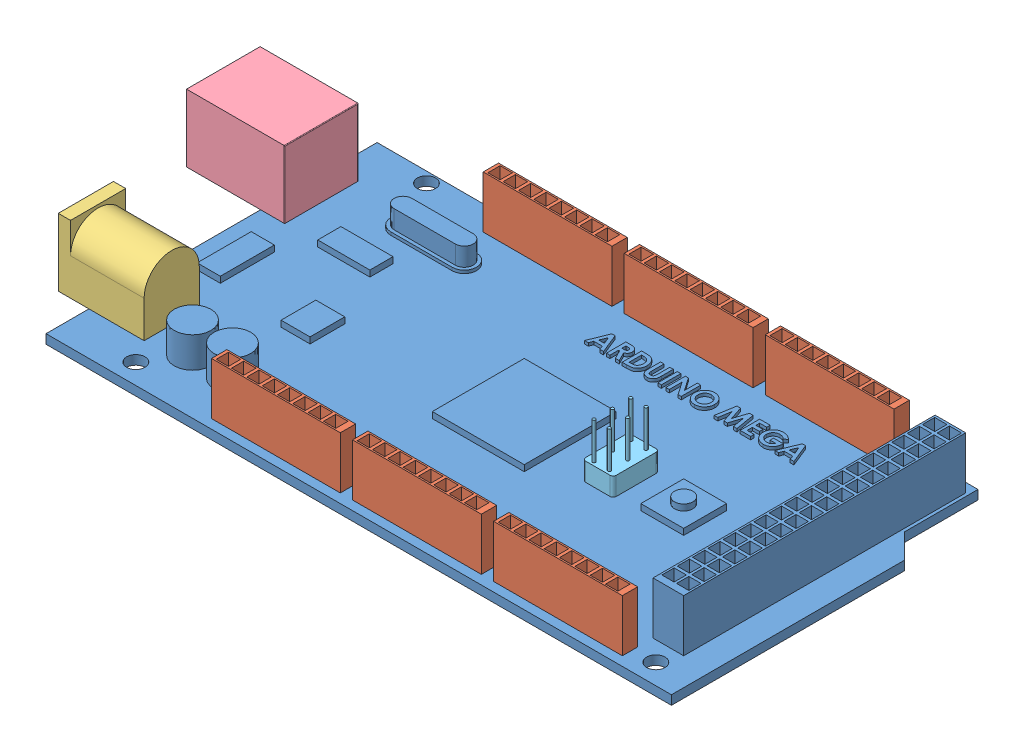
SolidWorks assembly Arduino Mega, configuration Default. Lengths in mm.
Overall size (114.08 12.5 54).
10 component instances, 5 part files, 27 mates.
Components (placement in the parent):
- 001-1: 001 [Default] at (51.0357 41.8477 79.1863) size (102 10 54)
- 002-1: 002 [Default] at (82.0357 43.3477 103.4363) size (21 8.5 2.5)
- 002-2: 002 [Default] at (59.0357 43.3477 103.4363) size (21 8.5 2.5)
- 002-3: 002 [Default] at (36.0357 43.3477 103.4363) size (21 8.5 2.5)
- 002-4: 002 [Default] at (77.8387 43.3477 54.9363) size (21 8.5 2.5)
- 002-5: 002 [Default] at (54.8387 43.3477 54.9363) size (21 8.5 2.5)
- 002-6: 002 [Default] at (31.8387 43.3477 54.9363) size (21 8.5 2.5)
- 003-1: 003 [Default] at (9.0357 48.8477 94.6863) x (0 0 1) z (-1 0 0) size (9 11 14)
- 004-1: 004 [Default] at (-4.0423 43.3477 65.1863) x (0 0 -1) z (1 0 0) size (12 11 16)
- 005-1: 005 [Default] at (67.0357 43.3477 79.4363) size (5 9 7.5)
Mates (geometry in assembly coordinates):
- Coincident1: coincident anti-aligned: plane of 001-1 through (51.0357 43.3477 79.1863) normal (0 1 0); plane of 002-2 through (59.0357 43.3477 103.4363) normal (0 -1 0)
- Coincident2: coincident anti-aligned: plane of 001-1 through (51.0357 43.3477 79.1863) normal (0 1 0); plane of 002-1 through (82.0357 43.3477 103.4363) normal (0 -1 0)
- Coincident3: coincident anti-aligned: plane of 001-1 through (51.0357 43.3477 79.1863) normal (0 1 0); plane of 002-3 through (36.0357 43.3477 103.4363) normal (0 -1 0)
- Distance2: distance = 1.5 mm aligned: plane of 002-1 through (71.5357 51.8477 104.6863) normal (0 0 1); plane of 001-1 through (0.0357 43.3477 106.1863) normal (0 0 1)
- Coincident6: coincident aligned: plane of 002-1 through (71.5357 51.8477 104.6863) normal (0 0 1); plane of 002-2 through (48.5357 51.8477 104.6863) normal (0 0 1)
- Coincident8: coincident aligned: plane of 002-2 through (48.5357 51.8477 104.6863) normal (0 0 1); plane of 002-3 through (25.5357 51.8477 104.6863) normal (0 0 1)
- Coincident9: coincident anti-aligned: plane of 001-1 through (51.0357 43.3477 79.1863) normal (0 1 0); plane of 002-4 through (77.8387 43.3477 54.9363) normal (0 -1 0)
- Coincident10: coincident anti-aligned: plane of 001-1 through (51.0357 43.3477 79.1863) normal (0 1 0); plane of 002-5 through (54.8387 43.3477 54.9363) normal (0 -1 0)
- Coincident11: coincident anti-aligned: plane of 001-1 through (51.0357 43.3477 79.1863) normal (0 1 0); plane of 002-6 through (31.8387 43.3477 54.9363) normal (0 -1 0)
- Coincident13: coincident anti-aligned: plane of 001-1 through (92.5357 51.8477 53.6863) normal (-1 0 0); plane of 002-1 through (92.5357 51.8477 102.1863) normal (1 0 0)
- Distance4: distance = 2 mm anti-aligned: plane of 002-2 through (69.5357 51.8477 102.1863) normal (1 0 0); plane of 002-1 through (71.5357 51.8477 102.1863) normal (-1 0 0)
- Distance5: distance = 2 mm anti-aligned: plane of 002-2 through (48.5357 51.8477 102.1863) normal (-1 0 0); plane of 002-3 through (46.5357 51.8477 102.1863) normal (1 0 0)
- Distance6: distance = 1.5 mm aligned: plane of 002-4 through (67.3387 51.8477 53.6863) normal (0 0 -1); plane of 001-1 through (0.0357 43.3477 52.1863) normal (0 0 -1)
- Distance7: distance = 4.5 mm: plane of 002-4 through (88.3387 51.8477 53.6863) normal (1 0 0); point of 001-1
- Coincident18: coincident aligned: plane of 002-4 through (67.3387 51.8477 53.6863) normal (0 0 -1); plane of 002-5 through (44.3387 51.8477 53.6863) normal (0 0 -1)
- Distance8: distance = 2 mm anti-aligned: plane of 002-4 through (67.3387 51.8477 53.6863) normal (-1 0 0); plane of 002-5 through (65.3387 51.8477 53.6863) normal (1 0 0)
- Distance9: distance = 2 mm anti-aligned: plane of 002-6 through (42.3387 51.8477 53.6863) normal (1 0 0); plane of 002-5 through (44.3387 51.8477 53.6863) normal (-1 0 0)
- Coincident21: coincident aligned: plane of 002-5 through (44.3387 51.8477 53.6863) normal (0 0 -1); plane of 002-6 through (21.3387 51.8477 53.6863) normal (0 0 -1)
- Coincident23: coincident anti-aligned: plane of 001-1 through (51.0357 43.3477 79.1863) normal (0 1 0); plane of 003-1 through (-4.9643 43.3477 90.1863) normal (0 -1 0)
- Distance10: distance = 7 mm aligned: plane of 001-1 through (0.0357 43.3477 106.1863) normal (0 0 1); plane of 003-1 through (-4.9643 54.3477 99.1863) normal (0 0 1)
- Distance11: distance = 9 mm anti-aligned: plane of 003-1 through (9.0357 48.8477 94.6863) normal (1 0 0); plane of 001-1 through (0.0357 43.3477 52.1863) normal (-1 0 0)
- Coincident27: coincident anti-aligned: plane of 001-1 through (51.0357 43.3477 79.1863) normal (0 1 0); plane of 004-1 through (-4.0423 43.3477 65.1863) normal (0 -1 0)
- Distance12: distance = 7 mm aligned: plane of 001-1 through (0.0357 43.3477 52.1863) normal (0 0 -1); plane of 004-1 through (-12.0423 54.3477 59.1863) normal (0 0 -1)
- Distance13: distance = 6 mm anti-aligned: plane of 004-1 through (3.9577 54.3477 71.1863) normal (1 0 0); plane of 001-1 through (9.9577 44.3477 68.0118) normal (-1 0 0)
- Coincident30: coincident anti-aligned: plane of 001-1 through (51.0357 43.3477 79.1863) normal (0 1 0); plane of 005-1 through (69.0357 43.3477 76.1863) normal (0 -1 0)
- Distance14: distance = 6 mm anti-aligned: plane of 001-1 through (58.5357 44.3477 71.6863) normal (1 0 0); plane of 005-1 through (64.5357 46.3477 76.1863) normal (-1 0 0)
- Distance15: distance = 3.5 mm aligned: plane of 001-1 through (43.5357 44.3477 86.6863) normal (0 0 1); plane of 005-1 through (65.0357 46.3477 83.1863) normal (0 0 1)
